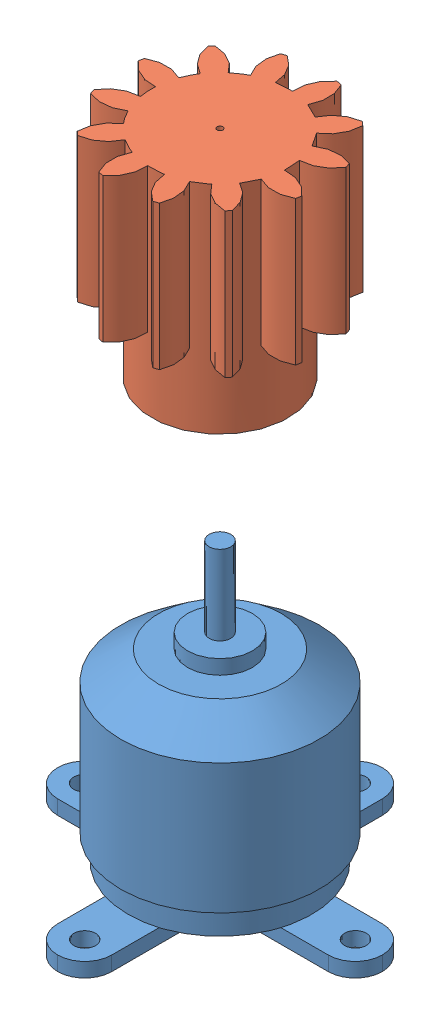
SolidWorks assembly Ensamblaje1, configuration Predeterminado. Lengths in mm.
Overall size (45 89.97 45).
2 component instances, 2 part files, 1 mates.
Components (placement in the parent):
- brushless A2212-1: brushless A2212 [Predeterminado] at origin size (45 40.5 45)
- Sun Gear - ISO - Spur gear 2M 12T 20PA 20FW-1: Sun Gear - ISO - Spur gear 2M 12T 20PA 20FW [ISO - Spur gear 2M 12T 20PA 20FW ---S12B19H30L0.8N] at (0 64.4677 0) x (0 1 0) z (-0.998211 0 0.059792) size (30 27.23 27.23)
Mates (geometry in assembly coordinates):
- Concéntrica1: concentric anti-aligned: circle of brushless A2212-1; circle of Sun Gear - ISO - Spur gear 2M 12T 20PA 20FW-1
